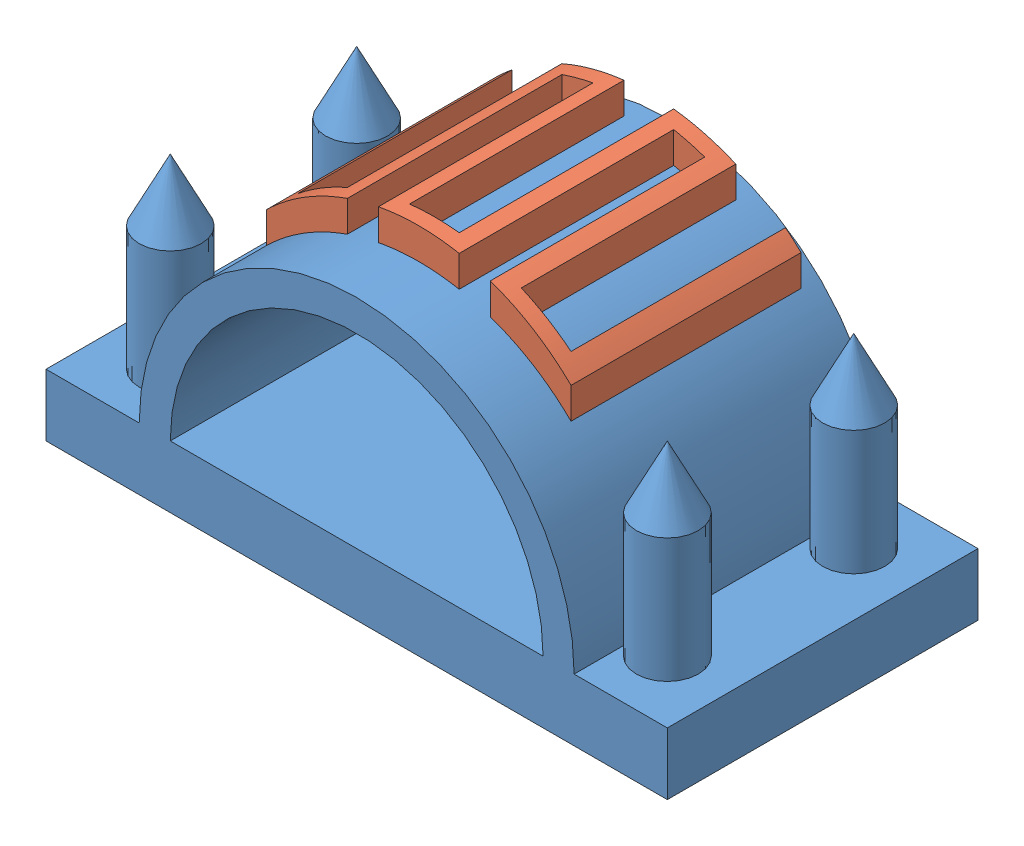
SolidWorks assembly Assem2, configuration Default. Lengths in mm.
Overall size (100 50.1 50).
2 component instances, 2 part files, 2 mates.
Components (placement in the parent):
- substrate_front-2: substrate_front [Default] at (50.8757 45.582 81.3094) x (1 0 0) z (0 1 0) size (100 50 45)
- 3d-print-top-1: 3d-print-top [Default] at (50.8773 55.5823 77.7583) size (49.02 15.12 37.47)
Mates (geometry in assembly coordinates):
- Tangent1: tangent: cylinder of assembly; cylinder of substrate_front-2 through (50.8757 55.582 184.5718) axis (0 0 -1) radius 35; face of 3d-print-top-1
- Distance1: distance = 10 mm aligned: plane of 3d-print-top-1 through (62.3773 88.639 96.3094) normal (0 0 1); plane of substrate_front-2 through (100.8757 55.582 106.3094) normal (0 0 1)
